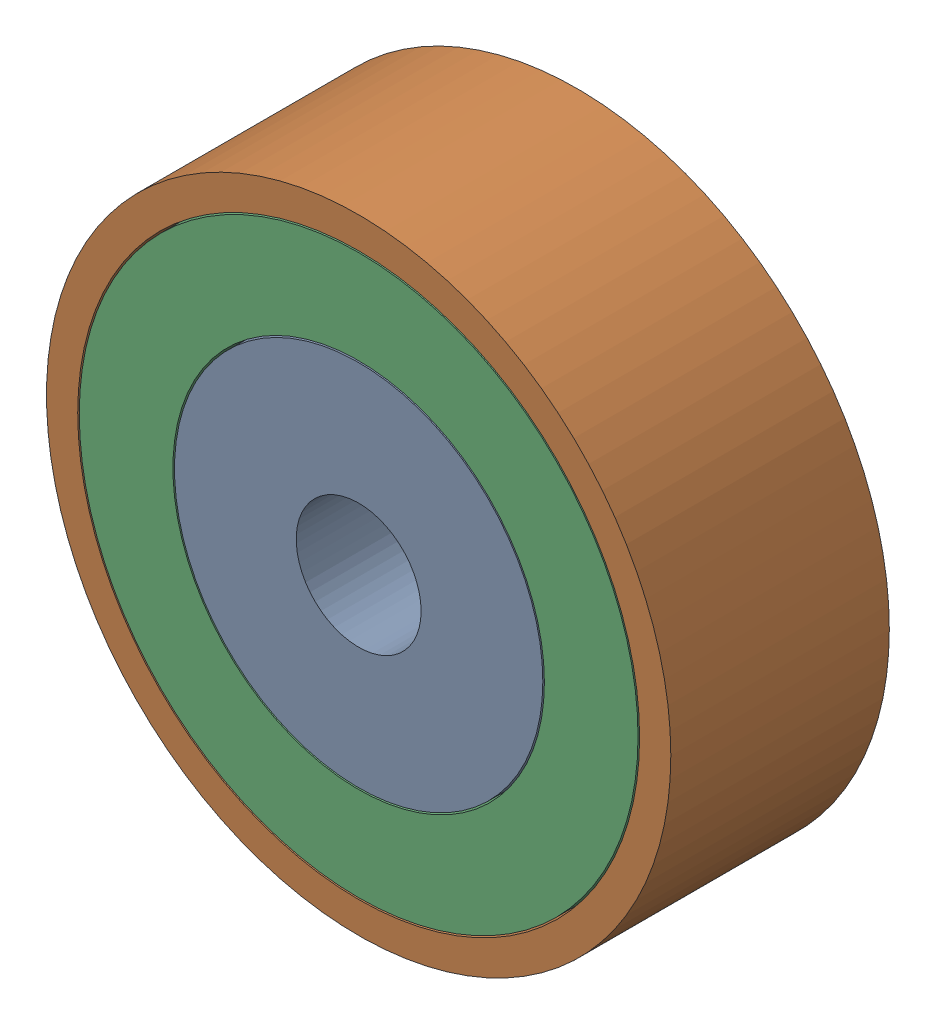
SolidWorks assembly 镜向轴承1, configuration 默认. Lengths in mm.
Overall size (20 20 7).
3 component instances, 3 part files, 4 mates.
Components (placement in the parent):
- 镜向轴承内圈-1: 镜向轴承内圈 [默认] at (-5.0655 0.8032 -6.5) size (11.8 11.8 7)
- 镜向轴承外圈-1: 镜向轴承外圈 [默认] at (-5.0655 0.8032 -6.5) size (20 20 7)
- 镜向轴承中圈-1: 镜向轴承中圈 [默认] at (-5.0655 0.8032 -6.5) size (17.9 17.9 7)
Mates (geometry in assembly coordinates):
- 重合1: coincident: plane of ? through (-5.0655 0.8032 -13.5) normal (0 0 -1); plane of ? through (-5.0655 0.8032 -13.5) normal (0 0 -1)
- 重合2: coincident: plane of ? through (-5.0655 0.8032 -13.5) normal (0 0 -1); plane of ? through (-5.0655 0.8032 -13.5) normal (0 0 -1)
- 同心1: concentric: cylinder of ? through (-5.0655 0.8032 -13.5) axis (0 0 1) radius 9; cylinder of ? through (-5.0655 0.8032 -13.5) axis (0 0 1) radius 8.95
- 同心2: concentric: cylinder of ? through (-5.0655 0.8032 -13.5) axis (0 0 1) radius 5.9; cylinder of ? through (-5.0655 0.8032 -13.5) axis (0 0 1) radius 5.95
